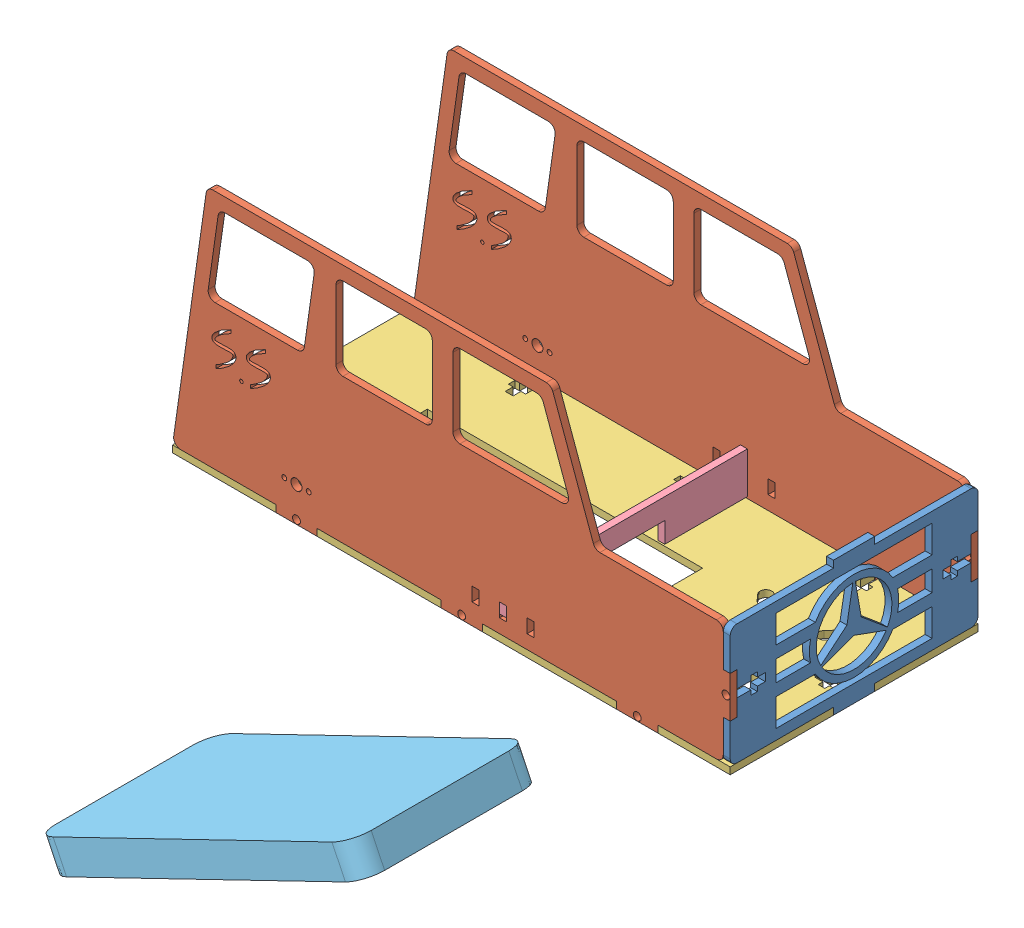
SolidWorks assembly CarModel, configuration Default. Lengths in mm.
Overall size (239.78 91.44 260.58).
6 component instances, 5 part files, 17 mates.
Components (placement in the parent):
- CarFront-1: CarFront [Default] at (59.0625 45.7761 57.682) size (2.54 49.53 91.44)
- CarSide-1: CarSide [Default] at (-67.9375 68.0011 100.862) size (205.35 91.44 2.54)
- CarSide-2: CarSide [Default] at (-67.9375 68.0011 11.962) size (205.35 91.44 2.54)
- Chassis-2: Chassis [Default] at (-41.2675 23.5511 57.682) size (205.74 2.54 91.44)
- Slide-1: Slide [Default] at (-23.4875 31.8061 57.682) size (2.54 15.24 91.44)
- Phone-1: Phone [Default] at (37.35 60.0295 239.5195) x (0 0 -1) z (-0.435748 0.900069 0) size (66.04 129.54 11.43)
Mates (geometry in assembly coordinates):
- Coincident2: coincident anti-aligned: plane of CarFront-1 through (59.0625 45.7761 57.682) normal (-1 0 0); plane of CarSide-1 through (59.0625 68.0011 103.402) normal (1 0 0)
- Coincident3: coincident anti-aligned: plane of CarFront-1 through (61.6025 38.1561 100.862) normal (0 1 0); plane of CarSide-1 through (61.6025 38.1561 103.402) normal (0 -1 0)
- Coincident4: coincident anti-aligned: plane of CarFront-1 through (61.6025 53.3961 11.962) normal (0 -1 0); plane of CarSide-2 through (59.0625 53.3961 14.502) normal (0 1 0)
- Coincident5: coincident anti-aligned: plane of CarFront-1 through (59.0625 45.7761 57.682) normal (-1 0 0); plane of CarSide-2 through (59.0625 68.0011 14.502) normal (1 0 0)
- Coincident6: coincident anti-aligned: plane of CarFront-1 through (61.6025 38.1561 14.502) normal (0 1 0); plane of CarSide-2 through (61.6025 38.1561 14.502) normal (0 -1 0)
- Coincident12: coincident anti-aligned: plane of CarSide-2 through (34.9325 23.5511 14.502) normal (0 -1 0); plane of Chassis-2 through (-41.2675 23.5511 57.682) normal (0 1 0)
- Coincident15: coincident anti-aligned: plane of CarFront-1 through (61.6025 21.0111 50.062) normal (0 0 -1); plane of Chassis-2 through (61.6025 21.0111 50.062) normal (0 0 1)
- Coincident16: coincident anti-aligned: plane of CarFront-1 through (59.0625 45.7761 57.682) normal (-1 0 0); plane of Chassis-2 through (59.0625 21.0111 59.1298) normal (1 0 0)
- Coincident17: coincident anti-aligned: plane of CarFront-1 through (61.6025 53.3961 14.502) normal (0 0 -1); plane of CarSide-2 through (-67.9375 68.0011 14.502) normal (0 0 1)
- Coincident18: coincident anti-aligned: plane of CarFront-1 through (61.6025 53.3961 100.862) normal (0 0 1); plane of CarSide-1 through (-67.9375 68.0011 100.862) normal (0 0 -1)
- Coincident19: coincident anti-aligned: plane of CarSide-1 through (-23.4875 33.7111 100.861) normal (0 -1 0); plane of Slide-1 through (-20.9475 33.7111 100.862) normal (0 1 0)
- Coincident20: coincident anti-aligned: plane of CarSide-2 through (-23.4875 33.7111 11.961) normal (0 -1 0); plane of Slide-1 through (-20.9475 33.7111 14.502) normal (0 1 0)
- Coincident21: coincident anti-aligned: plane of CarSide-2 through (-20.9475 33.7111 11.961) normal (-1 0 0); plane of Slide-1 through (-20.9475 31.8061 57.682) normal (1 0 0)
- Coincident22: coincident anti-aligned: plane of CarSide-1 through (-20.9475 33.7111 100.861) normal (-1 0 0); plane of Slide-1 through (-20.9475 31.8061 57.682) normal (1 0 0)
- Coincident23: coincident anti-aligned: plane of CarSide-1 through (-67.9375 68.0011 100.862) normal (0 0 -1); plane of Slide-1 through (-20.9475 39.4261 100.862) normal (0 0 1)
- Coincident28: coincident aligned: line of Slide-1 through (-20.9475 31.8061 44.982) axis (0 0 1); line of Phone-1 through (-20.9475 31.8061 214.1195) axis (0 0 1)
- Coincident29: coincident: line of CarFront-1 through (59.0625 70.5411 50.062) axis (0 0 1); plane of Phone-1 through (37.35 60.0295 239.5195) normal (0.435748 -0.900069 0)
